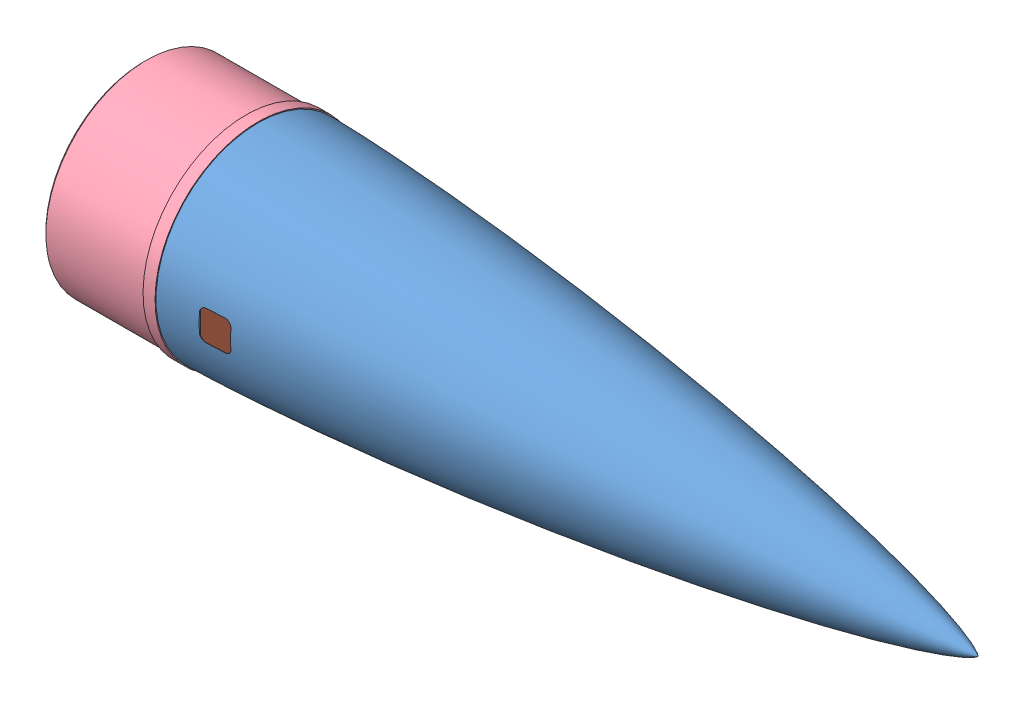
SolidWorks assembly Nosecone Assembly, configuration Default. Lengths in mm.
Overall size (695.08 206.96 206.96).
17 component instances, 11 part files, 27 mates.
Components (placement in the parent):
- Nosecone Prototype v5-1: Nosecone Prototype v5 [Default] at origin size (600.08 170 170.36)
- Nosecone Tap Insert-1: Nosecone Tap Insert [99362A500] at (10.691 34.775 60.2321) x (0 1 0) z (0 0 1) size (7.72 10.12 7.66)
- Nosecone Plate Screw-1: Nosecone Plate Screw [92949A245] at (-12.5654 50.7143 48.25) x (0 0 1) z (-1 0 0) size (9.17 9.17 22.21)
- NoseBottom-1: NoseBottom [Default] x (0 0.234694 -0.972069) z (1 0 0) size (171.5 171.5 95)
- Eggfinder tx-1: Eggfinder tx [Default] at (3 13.2486 54.4479) x (0 -0.845156 -0.53452) z (0 -0.53452 0.845156) size (79.57 81.62 22.8)
- gps mount-1: gps mount [Default] at (0 -41.7071 -7.4046) x (0 0.845156 0.53452) z (0 0.53452 -0.845156) size (82 4 25)
- battery-1: battery [Default] at (10 -9.8299 -64.9809) x (0 -0.53452 0.845156) z (0 -0.845156 -0.53452) size (55.7 10 30.6)
- battery holders-1: battery holders [Default] at (0 -42.362 -17.2845) x (0 0.53452 -0.845156) z (0 -0.845156 -0.53452) size (21 14 21)
- battery holders-2: battery holders [Default] at (0 18.7912 -49.2459) x (0 -0.53452 0.845156) z (0 0.845156 0.53452) size (21 14 21)
- GoPro Session-1: GoPro Session [Default] at (48.0195 0 57.5859) x (0 -1 0) z (-0.034899 0 0.999391) size (38 38 36.25)
- eyebolt-1: eyebolt [Default] at (-7.3 0 0) x (0 0.181829 -0.98333) z (0 0.98333 0.181829) size (15.53 64.67 49.98)
- Nosecone Tap Insert-12: Nosecone Tap Insert [99362A500] at (10.691 69.55 0) x (0 0.5 -0.866025) z (0 0.866025 0.5) size (7.72 10.12 7.66)
- Nosecone Tap Insert-13: Nosecone Tap Insert [99362A500] at (10.691 34.775 -60.2321) x (0 -0.5 -0.866025) z (0 0.866025 -0.5) size (7.72 10.12 7.66)
- Nosecone Tap Insert-14: Nosecone Tap Insert [99362A500] at (10.691 -34.775 -60.2321) x (0 -1 0) z (0 0 -1) size (7.72 10.12 7.66)
- Nosecone Tap Insert-15: Nosecone Tap Insert [99362A500] at (10.691 -69.55 0) x (0 -0.5 0.866025) z (0 -0.866025 -0.5) size (7.72 10.12 7.66)
- Nosecone Tap Insert-16: Nosecone Tap Insert [99362A500] at (10.691 -34.775 60.2321) x (0 0.5 0.866025) z (0 -0.866025 0.5) size (7.72 10.12 7.66)
- GoPro window-1: GoPro window [Default] at (34.8897 -12.5 82.9627) x (0.99863 0 -0.052336) z (0 1 0) size (25 3.17 25)
Mates (geometry in assembly coordinates):
- Lock1: lock: unknown of Nosecone Prototype v5-1; unknown of Nosecone Tap Insert-1
- Coincident12: coincident anti-aligned: plane of Nosecone Plate Screw-1 through (-10 46.1296 48.25) normal (1 0 0); plane of NoseBottom-1 through (-10 17.5 30.3109) normal (-1 0 0)
- Concentric17: concentric aligned: circle of Nosecone Plate Screw-1; cylinder of NoseBottom-1 through (0 50.7143 48.25) axis (-1 0 0) radius 2.75
- Coincident13: coincident anti-aligned: plane of NoseBottom-1 through (0 -20.125 83.3549) normal (1 0 0); plane of gps mount-1 through (0 -41.7071 -7.4046) normal (-1 0 0)
- Concentric18: concentric aligned: cylinder of Eggfinder tx-1 through (4.62 -45.6673 3.6978) axis (-1 0 0) radius 1.65; cylinder of gps mount-1 through (3 -45.6673 3.6978) axis (-1 0 0) radius 1.5875
- Coincident17: coincident anti-aligned: plane of NoseBottom-1 through (0 -20.125 83.3549) normal (1 0 0); plane of battery-1 through (0 -9.8299 -64.9809) normal (-1 0 0)
- Coincident19: coincident anti-aligned: plane of NoseBottom-1 through (0 -20.125 83.3549) normal (1 0 0); plane of battery holders-1 through (0 -42.362 -17.2845) normal (-1 0 0)
- Coincident21: coincident anti-aligned: plane of battery-1 through (0 -9.8299 -64.9809) normal (0 -0.845156 -0.53452); plane of battery holders-1 through (12 -40.6717 -16.2154) normal (0 0.845156 0.53452)
- Coincident22: coincident anti-aligned: plane of battery-1 through (0 -39.6027 -17.9057) normal (0 -0.53452 0.845156); plane of battery holders-1 through (12 -41.293 -18.9748) normal (0 0.53452 -0.845156)
- Coincident24: coincident anti-aligned: plane of NoseBottom-1 through (0 -20.125 83.3549) normal (1 0 0); plane of battery holders-2 through (0 18.7912 -49.2459) normal (-1 0 0)
- Coincident25: coincident anti-aligned: plane of battery-1 through (0 -9.8299 -64.9809) normal (0 0.53452 -0.845156); plane of battery holders-2 through (12 17.7221 -47.5556) normal (0 -0.53452 0.845156)
- Coincident26: coincident anti-aligned: plane of battery-1 through (0 16.0318 -48.6246) normal (0 0.845156 0.53452); plane of battery holders-2 through (12 17.1009 -50.3149) normal (0 -0.845156 -0.53452)
- Coincident38: coincident anti-aligned: plane of Eggfinder tx-1 through (3 13.2486 54.4479) normal (-1 0 0); plane of gps mount-1 through (3 -41.7071 -7.4046) normal (1 0 0)
- Parallel5: parallel anti-aligned: plane of Eggfinder tx-1 through (4.62 13.2486 54.4479) normal (0 -0.53452 0.845156); plane of gps mount-1 through (4 -54.0011 12.034) normal (0 0.53452 -0.845156)
- Concentric19: concentric aligned: cylinder of eyebolt-1 through (-26 0 0) axis (-1 0 0) radius 4.765; cylinder of NoseBottom-1 through (0 0 0) axis (-1 0 0) radius 3.9688
- Coincident39: coincident anti-aligned: plane of NoseBottom-1 through (-20 0 0) normal (-1 0 0); plane of eyebolt-1 through (-20 0.8664 -4.6856) normal (1 0 0)
- Distance1: distance = 9 mm anti-aligned: plane of gps mount-1 through (4 -41.1726 -8.2497) normal (0 0.53452 -0.845156); plane of battery-1 through (0 -39.6027 -17.9057) normal (0 -0.53452 0.845156)
- Coincident40: coincident anti-aligned: plane of Nosecone Prototype v5-1 through (28.3986 10.5 75.0368) normal (0.999391 0 0.034899); plane of GoPro Session-1 through (28.3986 -19 75.0368) normal (-0.999391 0 -0.034899)
- Concentric20: concentric aligned: cylinder of Nosecone Prototype v5-1 through (0 35 -60.6218) axis (-1 0 0) radius 3.3782; cylinder of NoseBottom-1 through (0 35 -60.6218) axis (-1 0 0) radius 5.5
- Concentric21: concentric aligned: cylinder of Nosecone Prototype v5-1 through (0 70 0) axis (-1 0 0) radius 3.3782; cylinder of NoseBottom-1 through (0 70 0) axis (-1 0 0) radius 5.5
- Concentric22: concentric aligned: cylinder of Nosecone Prototype v5-1 through (0 -35 60.6218) axis (-1 0 0) radius 3.3782; cylinder of NoseBottom-1 through (0 -35 60.6218) axis (-1 0 0) radius 5.5
- Coincident41: coincident anti-aligned: plane of Nosecone Prototype v5-1 through (0 75 0) normal (-1 0 0); plane of NoseBottom-1 through (0 -20.125 83.3549) normal (1 0 0)
- Coincident43: coincident anti-aligned: plane of Nosecone Prototype v5-1 through (36.8934 -19 75.3335) normal (0 1 0); plane of GoPro Session-1 through (28.3986 -19 75.0368) normal (0 -1 0)
- Coincident44: coincident aligned: circle of Nosecone Prototype v5-1; plane of GoPro Session-1 through (47.387 0 75.6999) normal (-0.034899 0 0.999391)
- Coincident45: coincident anti-aligned: plane of Nosecone Prototype v5-1 through (59.6893 7.5 78.4837) normal (-0.99863 0 0.052336); plane of GoPro window-1 through (59.6893 -12.5 78.4837) normal (0.99863 0 -0.052336)
- Coincident46: coincident anti-aligned: plane of Nosecone Prototype v5-1 through (39.7167 -12.5 79.5304) normal (0 1 0); plane of GoPro window-1 through (34.7236 -12.5 79.7921) normal (0 -1 0)
- Coincident47: coincident anti-aligned: plane of Nosecone Prototype v5-1 through (39.7167 7.5 79.5304) normal (0.052336 0 0.99863); plane of GoPro window-1 through (34.7236 -12.5 79.7921) normal (-0.052336 0 -0.99863)
